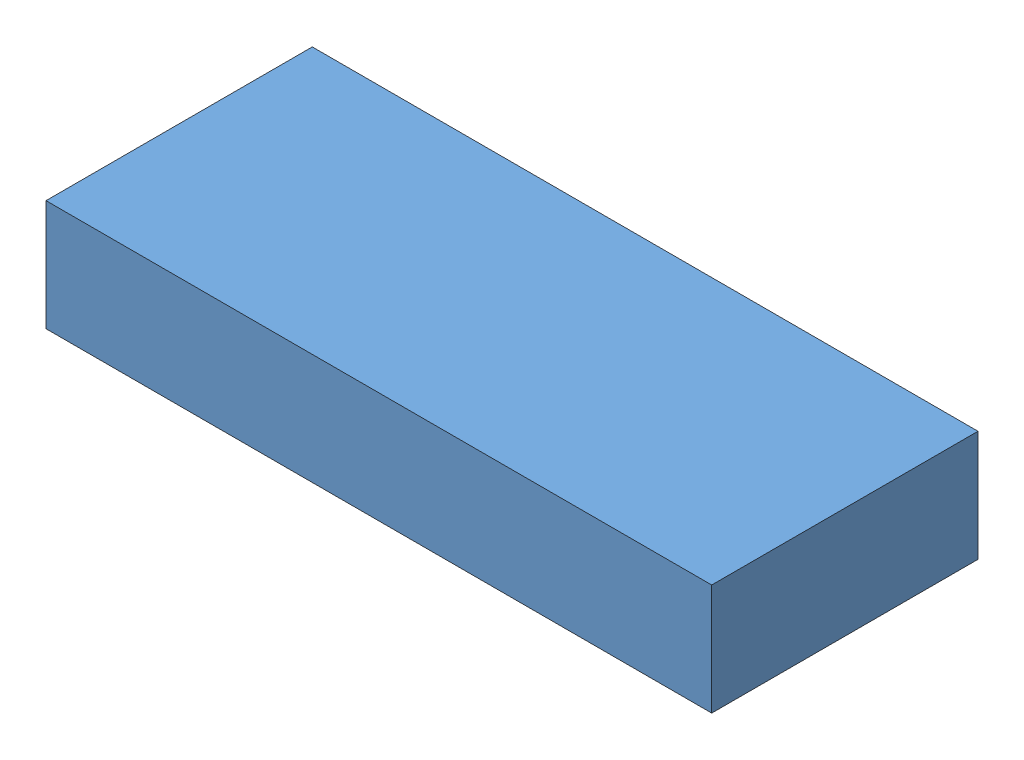
SolidWorks assembly Ensamblaje7, configuration Predeterminado. Lengths in mm.
Overall size (150 25 60).
2 component instances, 2 part files, 3 mates.
Components (placement in the parent):
- Pieza16-1: Pieza16 [Predeterminado] at (-218.8657 -60.3214 350) size (150 25 60)
- Pieza15-1: Pieza15 [Predeterminado] at (-168.8657 -55.3214 320) size (90 15 40)
Mates (geometry in assembly coordinates):
- Ancho1: width: plane of assembly; plane of assembly; plane of assembly; plane of assembly; plane of Pieza16-1 through (-218.8657 -35.3214 350) normal (0 0 1); plane of Pieza16-1 through (-218.8657 -35.3214 290) normal (0 0 -1); plane of Pieza15-1 through (-168.8657 -45.3214 300) normal (0 0 -1); plane of Pieza15-1 through (-168.8657 -45.3214 340) normal (0 0 1)
- Distancia1: distance = 20 mm: plane of assembly; line of assembly; plane of Pieza15-1 through (-168.8657 -40.3214 320) normal (0 1 0); line of Pieza16-1 through (-68.8657 -60.3214 290) axis (-1 0 0)
- Distancia2: distance = 40 mm: plane of assembly; plane of assembly; plane of Pieza15-1 through (-178.8657 -40.3214 314.2265) normal (-1 0 0); plane of Pieza16-1 through (-218.8657 -35.3214 350) normal (-1 0 0)
